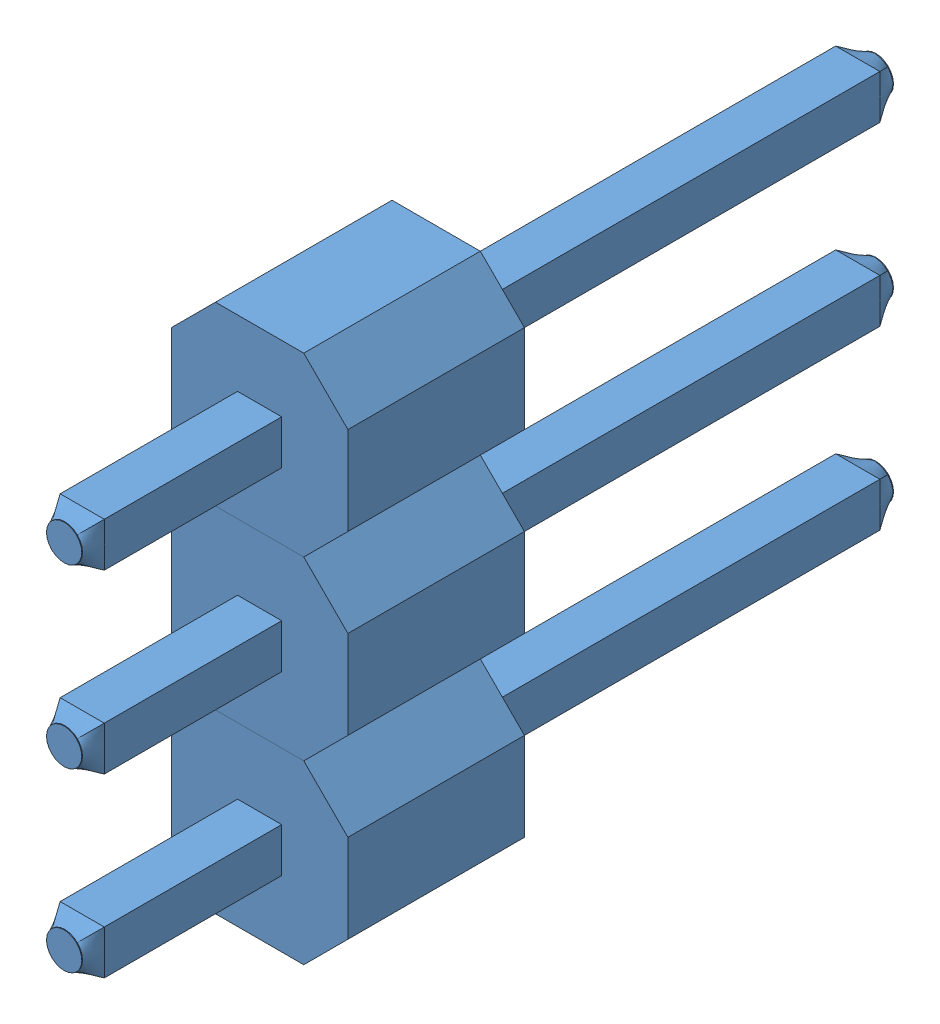
SolidWorks assembly Male Header 3 Pin, configuration Default. Lengths in mm.
Overall size (2.54 7.62 11.76).
3 component instances, 1 part files, 0 mates.
Components (placement in the parent):
- Male Header Pin-1: Male Header Pin [Default] at (-0.2347 1.0014 0.3576) size (2.54 2.54 11.76)
- Male Header Pin-2: Male Header Pin [Default] at (-0.2347 3.5414 0.3576) size (2.54 2.54 11.76)
- Male Header Pin-3: Male Header Pin [Default] at (-0.2347 6.0814 0.3576) size (2.54 2.54 11.76)
